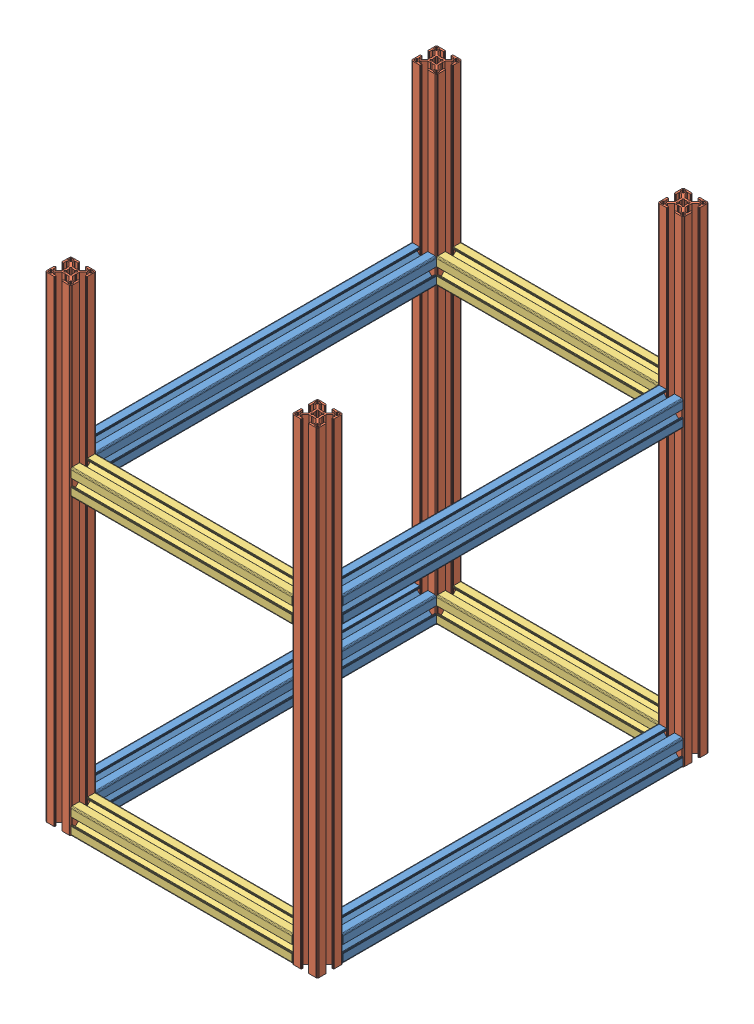
SolidWorks assembly module3_frame_v1.0, configuration Default. Lengths in mm.
Overall size (320 560 460).
12 component instances, 3 part files, 39 mates.
Components (placement in the parent):
- Profile_30x30mm_400mm-3: Profile_30x30mm_400mm [Default] x (1 0 0) z (0 0 -1) size (30 30 400)
- Profile_30x30mm_400mm-4: Profile_30x30mm_400mm [Default] at (-290 0 0) x (1 0 0) z (0 0 -1) size (30 30 400)
- profile_30x30mm_560mm-8: profile_30x30mm_560mm [Default] at (0 -30 -30) x (1 0 0) z (0 -1 0) size (30 30 560)
- profile_30x30mm_560mm-7: profile_30x30mm_560mm [Default] at (0 -30 400) x (1 0 0) z (0 -1 0) size (30 30 560)
- profile_30x30mm_560mm-5: profile_30x30mm_560mm [Default] at (-290 -30 -30) x (1 0 0) z (0 -1 0) size (30 30 560)
- profile_30x30mm_560mm-6: profile_30x30mm_560mm [Default] at (-290 -30 400) x (1 0 0) z (0 -1 0) size (30 30 560)
- profile_30x30mm_260mm-1: profile_30x30mm_260mm [Default] at (0 315 0) x (0 0 -1) z (1 0 0) size (30 30 260)
- profile_30x30mm_260mm-8: profile_30x30mm_260mm [Default] at (0 315 430) x (0 0 -1) z (1 0 0) size (30 30 260)
- profile_30x30mm_260mm-9: profile_30x30mm_260mm [Default] at (0 -30 430) x (0 0 -1) z (1 0 0) size (30 30 260)
- profile_30x30mm_260mm-7: profile_30x30mm_260mm [Default] at (0 -30 0) x (0 0 -1) z (1 0 0) size (30 30 260)
- Profile_30x30mm_400mm-6: Profile_30x30mm_400mm [Default] at (0 315 400) size (30 30 400)
- Profile_30x30mm_400mm-7: Profile_30x30mm_400mm [Default] at (-290 315 400) size (30 30 400)
Mates (geometry in assembly coordinates):
- Coincident1: coincident: plane of assembly; plane of assembly; plane of Profile_30x30mm_400mm-3 through (0 0 400) normal (0 0 1); plane of Profile_30x30mm_400mm-4 through (-290 0 400) normal (0 0 1)
- Coincident7: coincident: plane of assembly; plane of assembly; plane of Profile_30x30mm_400mm-3 through (10.25 -30 400) normal (0 -1 0); plane of Profile_30x30mm_400mm-4 through (-262 -30 400) normal (0 -1 0)
- Coincident24: coincident: plane of assembly; plane of assembly; plane of profile_30x30mm_560mm-8 through (0 -30 -30) normal (0 -1 0); plane of profile_30x30mm_560mm-7 through (0 -30 400) normal (0 -1 0)
- Coincident26: coincident: plane of assembly; plane of assembly; plane of profile_30x30mm_560mm-5 through (-290 -30 -30) normal (0 -1 0); plane of profile_30x30mm_560mm-6 through (-290 -30 400) normal (0 -1 0)
- Coincident27: coincident: plane of assembly; plane of assembly; plane of profile_30x30mm_560mm-5 through (-260 530 -10.25) normal (1 0 0); plane of profile_30x30mm_560mm-6 through (-260 530 419.75) normal (1 0 0)
- Coincident28: coincident: plane of assembly; plane of assembly; plane of profile_30x30mm_560mm-7 through (19.75 530 400) normal (0 0 -1); plane of profile_30x30mm_560mm-6 through (-288 530 400) normal (0 0 -1)
- Coincident30: coincident: plane of assembly; plane of assembly; plane of profile_30x30mm_560mm-8 through (10.25 530 0) normal (0 0 1); plane of profile_30x30mm_560mm-5 through (-279.75 530 0) normal (0 0 1)
- Coincident29: coincident: plane of assembly; plane of assembly; plane of profile_30x30mm_560mm-8 through (0 530 -19.75) normal (-1 0 0); plane of profile_30x30mm_560mm-7 through (0 530 428) normal (-1 0 0)
- Coincident32: coincident: plane of assembly; plane of assembly; plane of Profile_30x30mm_400mm-3 through (30 -2 400) normal (1 0 0); plane of profile_30x30mm_560mm-8 through (30 530 -28) normal (1 0 0)
- Coincident35: coincident: plane of assembly; plane of assembly; plane of Profile_30x30mm_400mm-4 through (-290 -10.25 400) normal (-1 0 0); plane of profile_30x30mm_560mm-6 through (-290 530 428) normal (-1 0 0)
- Coincident40: coincident: plane of assembly through (0 0 0) normal (0 0 1); plane of Profile_30x30mm_400mm-3 through (0 0 0) normal (0 0 -1); plane of assembly
- Coincident41: coincident: plane of assembly through (0 0 0) normal (0 1 0); plane of Profile_30x30mm_400mm-3 through (0 0 0) normal (0 -1 0); plane of assembly
- Coincident42: coincident: plane of assembly through (0 0 0) normal (1 0 0); plane of Profile_30x30mm_400mm-3 through (0 0 0) normal (1 0 0); plane of assembly
- Distance27: distance = 30 mm: plane of assembly; plane of assembly; plane of Profile_30x30mm_400mm-3 through (19.75 0 400) normal (0 1 0); plane of profile_30x30mm_560mm-8 through (0 -30 -30) normal (0 -1 0)
- Distance28: distance = 30 mm: plane of assembly; plane of assembly; plane of Profile_30x30mm_400mm-3 through (0 0 400) normal (0 0 1); plane of profile_30x30mm_560mm-7 through (10.25 530 430) normal (0 0 1)
- Coincident85: coincident: plane of assembly; plane of assembly; plane of profile_30x30mm_560mm-8 through (0 530 -19.75) normal (-1 0 0); plane of profile_30x30mm_260mm-1 through (0 315 0) normal (1 0 0)
- Coincident86: coincident: plane of profile_30x30mm_560mm-8 through (2 530 -30) normal (0 0 -1); plane of profile_30x30mm_260mm-1 through (-260 334.75 -30) normal (0 0 -1)
- Coincident88: coincident: plane of profile_30x30mm_560mm-5 through (-260 530 -28) normal (1 0 0); plane of profile_30x30mm_260mm-1 through (-260 315 0) normal (-1 0 0)
- Coincident101: coincident: plane of assembly through (0 0 0) normal (0 0 1); plane of Profile_30x30mm_400mm-3 through (0 0 0) normal (0 0 -1); plane of assembly
- Coincident102: coincident: plane of assembly through (0 0 0) normal (0 1 0); plane of Profile_30x30mm_400mm-3 through (0 0 0) normal (0 -1 0); plane of assembly
- Coincident103: coincident: plane of assembly through (0 0 0) normal (1 0 0); plane of Profile_30x30mm_400mm-3 through (0 0 0) normal (1 0 0); plane of assembly
- Coincident112: coincident: plane of assembly; plane of assembly; plane of profile_30x30mm_260mm-8 through (-260 315 430) normal (-1 0 0); plane of profile_30x30mm_260mm-9 through (-260 -30 430) normal (-1 0 0)
- Coincident113: coincident: plane of profile_30x30mm_260mm-9 through (-260 -30 430) normal (-1 0 0); plane of profile_30x30mm_260mm-7 through (-260 -30 0) normal (-1 0 0)
- Coincident114: coincident: plane of profile_30x30mm_260mm-9 through (-260 -30 410.25) normal (0 -1 0); plane of profile_30x30mm_260mm-7 through (-260 -30 -19.75) normal (0 -1 0)
- Coincident116: coincident: plane of profile_30x30mm_560mm-7 through (0 530 428) normal (-1 0 0); plane of profile_30x30mm_260mm-7 through (0 -30 0) normal (1 0 0)
- Coincident117: coincident: plane of profile_30x30mm_560mm-7 through (0 -30 400) normal (0 -1 0); plane of profile_30x30mm_260mm-9 through (-260 -30 428) normal (0 -1 0)
- Coincident118: coincident: plane of profile_30x30mm_560mm-7 through (28 530 430) normal (0 0 1); plane of profile_30x30mm_260mm-9 through (-260 -19.75 430) normal (0 0 1)
- Coincident119: coincident: plane of profile_30x30mm_560mm-8 through (19.75 530 -30) normal (0 0 -1); plane of profile_30x30mm_260mm-7 through (-260 -28 -30) normal (0 0 -1)
- Coincident120: coincident: plane of profile_30x30mm_560mm-7 through (28 530 430) normal (0 0 1); plane of profile_30x30mm_260mm-8 through (-260 343 430) normal (0 0 1)
- Distance43: distance = 185 mm: plane of profile_30x30mm_560mm-5 through (-290 530 -30) normal (0 1 0); plane of profile_30x30mm_260mm-1 through (-260 345 -10.25) normal (0 1 0)
- Coincident134: coincident: plane of profile_30x30mm_260mm-1 through (-260 345 -10.25) normal (0 1 0); plane of profile_30x30mm_260mm-8 through (-260 345 419.75) normal (0 1 0)
- Coincident236: coincident: plane of assembly; plane of assembly; plane of profile_30x30mm_560mm-7 through (0 -30 400) normal (0 -1 0); plane of profile_30x30mm_560mm-5 through (-290 -30 -30) normal (0 -1 0)
- Coincident247: coincident: plane of profile_30x30mm_260mm-8 through (-260 345 402) normal (0 1 0); plane of Profile_30x30mm_400mm-6 through (28 345 0) normal (0 1 0)
- Coincident248: coincident: plane of profile_30x30mm_560mm-7 through (2 530 400) normal (0 0 -1); plane of Profile_30x30mm_400mm-6 through (0 315 400) normal (0 0 1)
- Coincident249: coincident: plane of profile_30x30mm_560mm-7 through (30 530 419.75) normal (1 0 0); plane of Profile_30x30mm_400mm-6 through (30 334.75 0) normal (1 0 0)
- Coincident271: coincident: plane of assembly; plane of assembly; plane of profile_30x30mm_560mm-5 through (-262 530 0) normal (0 0 1); plane of Profile_30x30mm_400mm-7 through (-290 315 0) normal (0 0 -1)
- Coincident272: coincident: plane of Profile_30x30mm_400mm-6 through (19.75 315 0) normal (0 -1 0); plane of Profile_30x30mm_400mm-7 through (-270.25 315 0) normal (0 -1 0)
- Coincident273: coincident: plane of assembly; plane of assembly; plane of profile_30x30mm_560mm-5 through (-290 530 -2) normal (-1 0 0); plane of Profile_30x30mm_400mm-7 through (-290 343 0) normal (-1 0 0)
- Coincident274: coincident: plane of assembly; plane of assembly; plane of profile_30x30mm_560mm-6 through (-288 530 400) normal (0 0 -1); plane of Profile_30x30mm_400mm-7 through (-290 315 400) normal (0 0 1)
